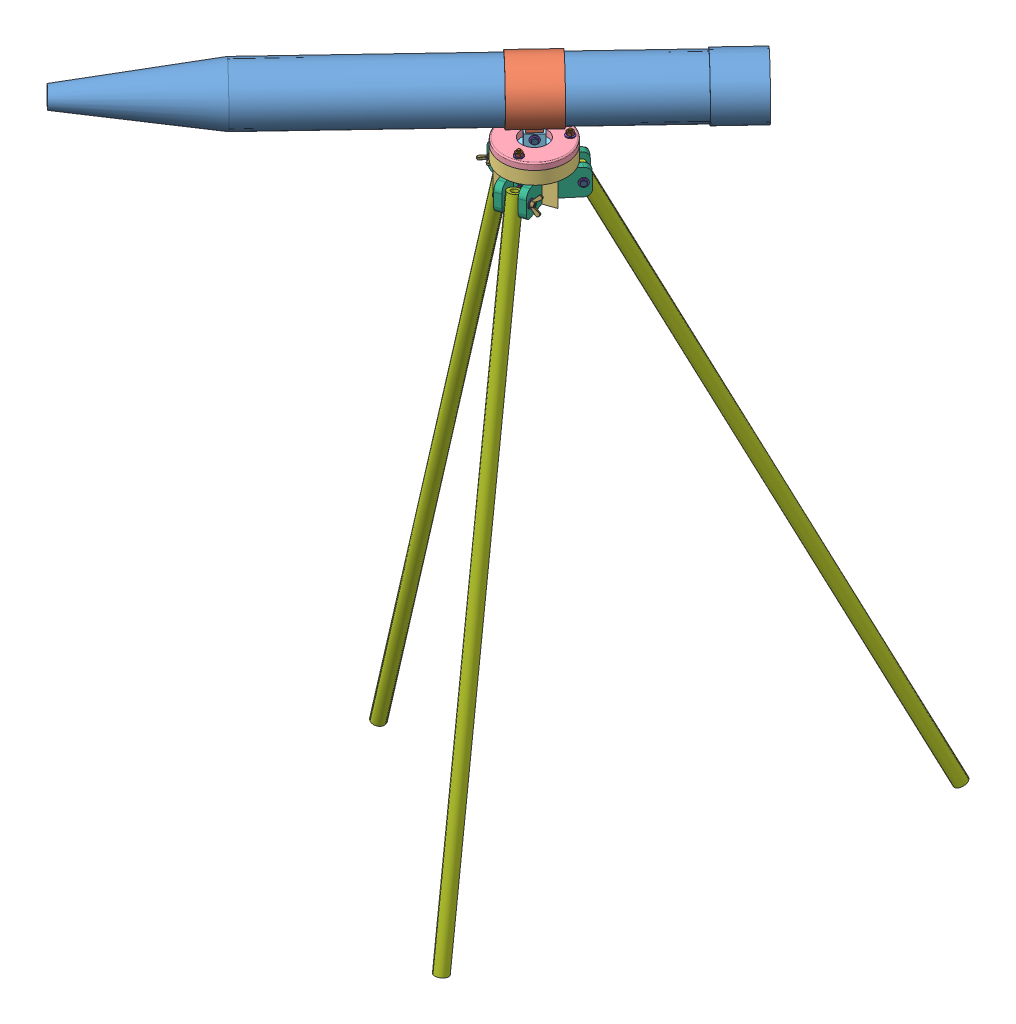
SolidWorks assembly ScopeAssembly, configuration Default. Lengths in mm.
Overall size (919.27 1388.64 1012.93).
45 component instances, 12 part files, 86 mates.
Components (placement in the parent):
- Scope-1: Scope [Default] at (13.0909 418.8257 1004.2832) x (-0.019653 -0.999634 -0.018601) z (0.726007 -0.02706 0.687155) size (111.76 1016 111.76)
- ScopeSupport-1: ScopeSupport [Default] at (455.0009 418.8257 537.3871) x (-0.726273 0 -0.687406) z (0.687406 0 -0.726273) size (113.03 157.48 84.67)
- RotatingDiskSeat-1: RotatingDiskSeat [Default] at (484.1011 298.1757 506.6415) x (0.762401 0 0.647105) z (-0.647105 0 0.762401) size (127 76.2 127)
- RotatingDiskLid-1: RotatingDiskLid [Default] at (484.1011 323.5757 506.6415) x (0.762401 0 0.647105) z (-0.647105 0 0.762401) size (127 12.7 127)
- RotatingDisk-1: RotatingDisk [Default] at (484.1011 310.8757 506.6415) x (0.687406 0 -0.726273) z (0.726273 0 0.687406) size (76.2 41.91 76.2)
- LegHinge-1: LegHinge [Default] at (502.5288 247.3757 558.1752) x (0.94161 0 -0.336706) z (0.336706 0 0.94161) size (50.8 50.8 50.8)
- LegHinge-2: LegHinge [Default] at (430.2577 298.1757 496.8335) x (0.179209 0 -0.983811) z (-0.983811 0 -0.179209) size (50.8 50.8 50.8)
- LegHinge-3: LegHinge [Default] at (519.5168 247.3757 464.9158) x (-0.762401 0 -0.647105) z (0.647105 0 -0.762401) size (50.8 50.8 50.8)
- Leg-1: Leg [Default] at (873.6454 -808.8425 47.6914) x (0.580125 0.443059 -0.683487) z (0.762401 0 0.647105) size (25.4 1219.2 25.4)
- Leg-2: Leg [Default] at (587.0814 -909.9329 794.6294) x (0.330066 0.19761 0.923042) z (-0.94161 0 0.336706) size (25.4 1219.2 25.4)
- Leg-3: Leg [Default] at (105.0997 -891.1144 437.6034) x (-0.949066 0.263414 -0.17288) z (0.179209 0 -0.983811) size (25.4 1219.2 25.4)
- flat washer type a narrow_ai-3: flat washer type a narrow_ai [Preferred Narrow FW 0.25] at (508.37 272.7757 438.7968) x (0.762401 0 0.647105) z (-0.647105 0 0.762401) size (1.65 15.88 15.88)
- flat washer type a narrow_ai-4: flat washer type a narrow_ai [Preferred Narrow FW 0.25] at (422.3152 272.7757 469.5687) x (-0.179209 0 0.983811) z (-0.983811 0 -0.179209) size (1.65 15.88 15.88)
- flat washer type a narrow_ai-5: flat washer type a narrow_ai [Preferred Narrow FW 0.25] at (530.7219 272.7757 561.5813) x (-0.94161 0 0.336706) z (-0.336706 0 -0.94161) size (1.65 15.88 15.88)
- flat washer type a narrow_ai-6: flat washer type a narrow_ai [Preferred Narrow FW 0.25] at (547.1 272.7757 471.6697) x (-0.762401 0 -0.647105) z (0.647105 0 -0.762401) size (1.65 15.88 15.88)
- flat washer type a narrow_ai-7: flat washer type a narrow_ai [Preferred Narrow FW 0.25] at (482.8881 272.7757 578.686) x (0.94161 0 -0.336706) z (0.336706 0 0.94161) size (1.65 15.88 15.88)
- flat washer type a narrow_ai-8: flat washer type a narrow_ai [Preferred Narrow FW 0.25] at (413.2114 272.7757 519.5463) x (0.179209 0 -0.983811) z (0.983811 0 0.179209) size (1.65 15.88 15.88)
- flat washer type a narrow_ai-9: flat washer type a narrow_ai [Preferred Narrow FW 0.25] at (442.7521 272.7757 499.1095) x (0.983811 0 0.179209) z (-0.179209 0 0.983811) size (1.65 15.88 15.88)
- flat washer type a narrow_ai-10: flat washer type a narrow_ai [Preferred Narrow FW 0.25] at (433.7081 298.1349 497.3786) x (0 1 0) z (0 0 1) size (1.65 15.88 15.88)
- flat washer type a narrow_ai-11: flat washer type a narrow_ai [Preferred Narrow FW 0.25] at (511.2985 272.7757 474.5982) x (-0.647105 0 0.762401) z (-0.762401 0 -0.647105) size (1.65 15.88 15.88)
- flat washer type a narrow_ai-12: flat washer type a narrow_ai [Preferred Narrow FW 0.25] at (516.974 298.1757 467.9115) x (0 1 0) z (0 0 1) size (1.65 15.88 15.88)
- flat washer type a narrow_ai-13: flat washer type a narrow_ai [Preferred Narrow FW 0.25] at (501.2058 298.1757 554.4753) x (0 1 0) z (0 0 1) size (1.65 15.88 15.88)
- flat washer type a narrow_ai-14: flat washer type a narrow_ai [Preferred Narrow FW 0.25] at (498.2526 272.7757 546.2168) x (-0.336706 0 -0.94161) z (0.94161 0 -0.336706) size (1.65 15.88 15.88)
- flat washer type a narrow_ai-15: flat washer type a narrow_ai [Preferred Narrow FW 0.25] at (501.2058 336.2757 554.4753) x (0 -1 0) z (0 0 1) size (1.65 15.88 15.88)
- flat washer type a narrow_ai-16: flat washer type a narrow_ai [Preferred Narrow FW 0.25] at (516.974 336.2757 467.9115) x (0 -1 0) z (0 0 1) size (1.65 15.88 15.88)
- flat washer type a narrow_ai-17: flat washer type a narrow_ai [Preferred Narrow FW 0.25] at (434.1235 336.2757 497.5377) x (0 -1 0) z (0 0 1) size (1.65 15.88 15.88)
- flat washer type a narrow_ai-18: flat washer type a narrow_ai [Preferred Narrow FW 0.25] at (472.5715 343.2607 495.7289) x (0.726273 0 0.687406) z (-0.687406 0 0.726273) size (1.65 15.88 15.88)
- flat washer type a narrow_ai-21: flat washer type a narrow_ai [Preferred Narrow FW 0.25] at (495.6307 343.2607 517.5541) x (-0.726273 0 -0.687406) z (0.687406 0 -0.726273) size (1.65 15.88 15.88)
- hex bolt_ai-7: hex bolt_ai [HBOLT 0.2500-20x2x0.75-N] at (433.7081 291.7087 497.3786) x (0 1 0) z (0 0 1) size (55.58 12.85 11.13)
- hex bolt_ai-8: hex bolt_ai [HBOLT 0.2500-20x2x0.75-N] at (516.974 291.7495 467.9115) x (0 1 0) z (0 0 1) size (55.58 12.85 11.13)
- hex bolt_ai-9: hex bolt_ai [HBOLT 0.2500-20x2x0.75-N] at (501.2058 291.7495 554.4753) x (0 1 0) z (0 0 1) size (55.58 12.85 11.13)
- hexagon head bolt (grade a)_ks-1: hexagon head bolt (grade a)_ks [KS 1002 A - M6 x 60 x 18-N] at (550.1496 272.7757 474.2582) x (-0.762401 0 -0.647105) z (0.647105 0 -0.762401) size (64 11.55 10)
- hexagon head bolt (grade a)_ks-2: hexagon head bolt (grade a)_ks [KS 1002 A - M6 x 60 x 18-N] at (423.0321 272.7757 465.6335) x (-0.179209 0 0.983811) z (-0.983811 0 -0.179209) size (64 11.55 10)
- hexagon head bolt (grade a)_ks-3: hexagon head bolt (grade a)_ks [KS 1002 A - M6 x 60 x 18-N] at (477.567 272.7757 580.5887) x (0.94161 0 -0.336706) z (0.336706 0 0.94161) size (64 11.55 10)
- hexagon head bolt (grade a)_ks-4: hexagon head bolt (grade a)_ks [KS 1002 A - M6 x 45 x 18-N] at (499.7348 343.2607 521.4386) x (-0.726273 0 -0.687406) z (0.687406 0 -0.726273) size (49 11.55 10)
- hex bolt_ai-14: hex bolt_ai [HBOLT 0.2500-20x1x0.75-N] at (499.8605 272.7757 550.7132) x (-0.336706 0 -0.94161) z (0.94161 0 -0.336706) size (30.18 12.85 11.13)
- hex bolt_ai-15: hex bolt_ai [HBOLT 0.2500-20x1x0.75-N] at (436.4299 272.7757 497.9578) x (0.983811 0 0.179209) z (-0.179209 0 0.983811) size (30.18 12.85 11.13)
- hex bolt_ai-16: hex bolt_ai [HBOLT 0.2500-20x1x0.75-N] at (515.4569 272.7757 469.6989) x (-0.647105 0 0.762401) z (-0.762401 0 -0.647105) size (30.18 12.85 11.13)
- hex nut_ai-2: hex nut_ai [HNUT 0.2500-20-D-N] at (501.2058 343.6671 554.4753) x (1 0 0) z (0 1 0) size (11.11 12.83 5.74)
- hex nut_ai-3: hex nut_ai [HNUT 0.2500-20-D-N] at (516.974 338.4418 467.9115) x (1 0 0) z (0 -1 0) size (11.11 12.83 5.74)
- hex nut_ai-4: hex nut_ai [HNUT 0.2500-20-D-N] at (433.7081 338.1349 497.3786) x (1 0 0) z (0 -1 0) size (11.11 12.83 5.74)
- wing nut (class 1)_ks-4: wing nut (class 1)_ks [KS B 1014-98 C1 - M6-N] at (471.3724 343.2607 494.594) x (-0.566242 0.566972 0.598258) z (-0.38974 -0.823737 0.411776) size (32 16 10.5)
- wing nut (class 1)_ks-7: wing nut (class 1)_ks [KS B 1014-98 C1 - M6-N] at (532.2765 272.7757 561.0254) x (0.113371 -0.94161 0.317046) z (0.317046 0.336706 0.886629) size (32 16 10.5)
- wing nut (class 1)_ks-8: wing nut (class 1)_ks [KS B 1014-98 C1 - M6-N] at (507.1113 272.7757 437.7284) x (0.418745 0.762401 -0.493353) z (-0.493353 0.647105 0.581255) size (32 16 10.5)
- wing nut (class 1)_ks-10: wing nut (class 1)_ks [KS B 1014-98 C1 - M6-N] at (412.9155 272.7757 521.1706) x (0.967884 0.179209 0.176308) z (0.176308 -0.983811 0.032116) size (32 16 10.5)
Mates (geometry in assembly coordinates):
- Concentric2: concentric anti-aligned: cylinder of Scope-1 through (39.1928 418.8257 976.7055) axis (-0.687406 0 0.726273) radius 53.34; cylinder of ScopeSupport-1 through (455.0009 418.8257 537.3871) axis (0.687406 0 -0.726273) radius 53.34
- Concentric3: concentric anti-aligned: cylinder of ScopeSupport-1 through (525.1464 343.2607 545.4903) axis (-0.726273 0 -0.687406) radius 3.175; cylinder of RotatingDisk-1 through (456.4301 343.2607 480.4513) axis (0.726273 0 0.687406) radius 3.175
- Parallel1: parallel aligned: plane of ScopeSupport-1 through (455.0009 317.8607 537.3871) normal (0 -1 0); plane of RotatingDisk-1 through (484.1011 310.8757 506.6415) normal (0 -1 0)
- Coincident3: coincident anti-aligned: plane of ScopeSupport-1 through (503.9776 362.3107 467.1659) normal (-0.726273 0 -0.687406); plane of RotatingDisk-1 through (466.1474 310.8757 507.1351) normal (0.726273 0 0.687406)
- Concentric4: concentric anti-aligned: cylinder of RotatingDiskSeat-1 through (484.1011 310.8757 506.6415) axis (0 1 0) radius 38.1; cylinder of RotatingDisk-1 through (484.1011 321.0357 506.6415) axis (0 -1 0) radius 38.1
- Coincident6: coincident anti-aligned: plane of RotatingDiskSeat-1 through (484.1011 310.8757 506.6415) normal (0 1 0); plane of RotatingDisk-1 through (484.1011 310.8757 506.6415) normal (0 -1 0)
- Concentric6: concentric aligned: cylinder of RotatingDiskSeat-1 through (501.2058 247.3757 554.4753) axis (0 1 0) radius 3.175; cylinder of RotatingDiskLid-1 through (501.2058 323.5757 554.4753) axis (0 1 0) radius 3.175
- Concentric7: concentric aligned: cylinder of RotatingDiskSeat-1 through (484.1011 323.5757 506.6415) axis (0 -1 0) radius 63.5; cylinder of RotatingDiskLid-1 through (484.1011 336.2757 506.6415) axis (0 -1 0) radius 63.5
- Coincident7: coincident anti-aligned: plane of RotatingDiskSeat-1 through (484.1011 323.5757 506.6415) normal (0 1 0); plane of RotatingDiskLid-1 through (484.1011 323.5757 506.6415) normal (0 -1 0)
- Coincident8: coincident aligned: circle of RotatingDiskSeat-1; circle of LegHinge-1
- Coincident9: coincident aligned: plane of RotatingDiskSeat-1 through (484.1011 247.3757 506.6415) normal (0 -1 0); plane of LegHinge-1 through (502.5288 247.3757 558.1752) normal (0 -1 0)
- Coincident11: coincident aligned: circle of RotatingDiskSeat-1; circle of LegHinge-2
- Coincident12: coincident anti-aligned: circle of RotatingDiskSeat-1; circle of LegHinge-3
- Coincident13: coincident aligned: plane of RotatingDiskSeat-1 through (484.1011 247.3757 506.6415) normal (0 -1 0); plane of LegHinge-2 through (430.2577 247.3757 496.8335) normal (0 -1 0)
- Coincident14: coincident aligned: plane of RotatingDiskSeat-1 through (484.1011 247.3757 506.6415) normal (0 -1 0); plane of LegHinge-3 through (519.5168 247.3757 464.9158) normal (0 -1 0)
- Concentric8: concentric anti-aligned: cylinder of LegHinge-1 through (482.8881 272.7757 578.686) axis (0.94161 0 -0.336706) radius 3.175; cylinder of Leg-2 through (518.7634 272.7757 565.8575) axis (-0.94161 0 0.336706) radius 3.175
- Width1: width: plane of LegHinge-1 through (499.1227 247.3757 586.3683) normal (0.94161 0 -0.336706); plane of LegHinge-1 through (523.0396 247.3757 577.816) normal (-0.94161 0 0.336706); cylinder of Leg-2 through (505.96 285.2252 567.7706) axis (0.066537 -0.980281 0.186072) radius 12.7
- Width2: width: plane of LegHinge-2 through (407.5449 298.1757 479.7872) normal (-0.179209 0 0.983811); plane of LegHinge-2 through (402.993 298.1757 504.776) normal (0.179209 0 -0.983811); cylinder of Leg-3 through (421.0545 285.0271 495.1571) axis (-0.259149 -0.964683 -0.047206) radius 12.7
- Width3: width: plane of LegHinge-3 through (545.6357 247.3757 453.769) normal (-0.762401 0 -0.647105); plane of LegHinge-3 through (526.2707 247.3757 437.3325) normal (0.762401 0 0.647105); cylinder of Leg-1 through (524.0938 284.1611 459.5232) axis (0.286706 -0.896492 -0.337789) radius 12.7
- Concentric9: concentric anti-aligned: cylinder of LegHinge-3 through (547.1 272.7757 471.6697) axis (-0.762401 0 -0.647105) radius 3.175; cylinder of Leg-1 through (518.0525 272.7757 447.015) axis (0.762401 0 0.647105) radius 3.175
- Concentric10: concentric aligned: cylinder of LegHinge-2 through (413.2114 272.7757 519.5463) axis (0.179209 0 -0.983811) radius 3.175; cylinder of Leg-3 through (415.4874 272.7757 507.0519) axis (0.179209 0 -0.983811) radius 3.175
- LimitDistance1: limit distance = 203.8008 mm anti-aligned: plane of ScopeSupport-1 through (513.2013 418.8257 475.8959) normal (0.687406 0 -0.726273); plane of Scope-1 through (652.197 362.9661 326.8414) normal (-0.687406 0 0.726273)
- Concentric11: concentric aligned: cylinder of LegHinge-3 through (547.1 272.7757 471.6697) axis (-0.762401 0 -0.647105) radius 3.175; cylinder of flat washer type a narrow_ai-3 through (481.7432 272.7757 416.1967) axis (-0.762401 0 -0.647105) radius 3.5687
- Coincident15: coincident anti-aligned: plane of LegHinge-3 through (516.5882 298.1757 429.1143) normal (-0.762401 0 -0.647105); plane of flat washer type a narrow_ai-3 through (508.37 276.3444 438.7968) normal (0.762401 0 0.647105)
- Concentric12: concentric aligned: cylinder of LegHinge-2 through (413.2114 272.7757 519.5463) axis (0.179209 0 -0.983811) radius 3.175; cylinder of flat washer type a narrow_ai-4 through (428.5741 272.7757 435.2091) axis (0.179209 0 -0.983811) radius 3.5687
- Coincident16: coincident anti-aligned: plane of LegHinge-2 through (409.8208 247.3757 467.2928) normal (0.179209 0 -0.983811); plane of flat washer type a narrow_ai-4 through (422.3152 276.3444 469.5687) normal (-0.179209 0 0.983811)
- Concentric13: concentric aligned: cylinder of LegHinge-1 through (482.8881 272.7757 578.686) axis (0.94161 0 -0.336706) radius 3.175; cylinder of flat washer type a narrow_ai-5 through (563.6076 272.7757 549.8219) axis (0.94161 0 -0.336706) radius 3.5687
- Coincident17: coincident anti-aligned: plane of LegHinge-1 through (534.998 298.1757 573.5398) normal (0.94161 0 -0.336706); plane of flat washer type a narrow_ai-5 through (530.7219 276.3444 561.5813) normal (-0.94161 0 0.336706)
- Concentric14: concentric anti-aligned: cylinder of LegHinge-3 through (547.1 272.7757 471.6697) axis (-0.762401 0 -0.647105) radius 3.175; cylinder of flat washer type a narrow_ai-6 through (573.7268 272.7757 494.2699) axis (0.762401 0 0.647105) radius 3.5687
- Coincident18: coincident anti-aligned: plane of LegHinge-3 through (555.3182 298.1757 461.9872) normal (0.762401 0 0.647105); plane of flat washer type a narrow_ai-6 through (547.1 276.3444 471.6697) normal (-0.762401 0 -0.647105)
- Concentric15: concentric anti-aligned: cylinder of LegHinge-1 through (482.8881 272.7757 578.686) axis (0.94161 0 -0.336706) radius 3.175; cylinder of flat washer type a narrow_ai-7 through (450.0024 272.7757 590.4455) axis (-0.94161 0 0.336706) radius 3.5687
- Coincident19: coincident anti-aligned: plane of LegHinge-1 through (487.1642 298.1757 590.6445) normal (-0.94161 0 0.336706); plane of flat washer type a narrow_ai-7 through (482.8881 276.3444 578.686) normal (0.94161 0 -0.336706)
- Concentric16: concentric anti-aligned: cylinder of LegHinge-2 through (413.2114 272.7757 519.5463) axis (0.179209 0 -0.983811) radius 3.175; cylinder of flat washer type a narrow_ai-8 through (406.9525 272.7757 553.9059) axis (-0.179209 0 0.983811) radius 3.5687
- Coincident20: coincident anti-aligned: plane of LegHinge-2 through (400.717 247.3757 517.2704) normal (-0.179209 0 0.983811); plane of flat washer type a narrow_ai-8 through (413.2114 276.3444 519.5463) normal (0.179209 0 -0.983811)
- Concentric17: concentric aligned: cylinder of LegHinge-2 through (455.2465 272.7757 501.3854) axis (-0.983811 0 -0.179209) radius 3.175; cylinder of flat washer type a narrow_ai-9 through (408.3925 272.7757 492.8506) axis (-0.983811 0 -0.179209) radius 3.5687
- Coincident21: coincident anti-aligned: plane of LegHinge-2 through (440.4762 298.1757 511.6039) normal (-0.983811 0 -0.179209); plane of flat washer type a narrow_ai-9 through (442.7521 276.3444 499.1095) normal (0.983811 0 0.179209)
- Concentric18: concentric aligned: cylinder of LegHinge-3 through (503.0803 272.7757 484.2807) axis (0.647105 0 -0.762401) radius 3.175; cylinder of flat washer type a narrow_ai-11 through (533.8987 272.7757 447.9714) axis (0.647105 0 -0.762401) radius 3.5687
- Coincident22: coincident anti-aligned: plane of LegHinge-3 through (520.981 247.3757 482.8165) normal (0.647105 0 -0.762401); plane of flat washer type a narrow_ai-11 through (511.2985 276.3444 474.5982) normal (-0.647105 0 0.762401)
- Concentric19: concentric anti-aligned: cylinder of RotatingDiskSeat-1 through (516.974 247.3757 467.9115) axis (0 1 0) radius 3.175; cylinder of flat washer type a narrow_ai-12 through (516.974 263.2507 467.9115) axis (0 -1 0) radius 3.5687
- Coincident23: coincident anti-aligned: plane of RotatingDiskSeat-1 through (484.1011 298.1757 506.6415) normal (0 -1 0); plane of flat washer type a narrow_ai-12 through (513.4053 298.1757 467.9115) normal (0 1 0)
- Concentric20: concentric anti-aligned: cylinder of RotatingDiskSeat-1 through (501.2058 247.3757 554.4753) axis (0 1 0) radius 3.175; cylinder of flat washer type a narrow_ai-13 through (501.2058 263.2507 554.4753) axis (0 -1 0) radius 3.5687
- Coincident24: coincident anti-aligned: plane of RotatingDiskSeat-1 through (484.1011 298.1757 506.6415) normal (0 -1 0); plane of flat washer type a narrow_ai-13 through (497.6371 298.1757 554.4753) normal (0 1 0)
- Concentric21: concentric aligned: cylinder of LegHinge-1 through (493.9765 272.7757 534.2583) axis (0.336706 0 0.94161) radius 3.175; cylinder of flat washer type a narrow_ai-14 through (510.0121 272.7757 579.1025) axis (0.336706 0 0.94161) radius 3.5687
- Coincident25: coincident anti-aligned: plane of LegHinge-1 through (486.2942 247.3757 550.493) normal (0.336706 0 0.94161); plane of flat washer type a narrow_ai-14 through (498.2526 276.3444 546.2168) normal (-0.336706 0 -0.94161)
- Concentric22: concentric aligned: cylinder of RotatingDiskLid-1 through (501.2058 323.5757 554.4753) axis (0 1 0) radius 3.175; cylinder of flat washer type a narrow_ai-15 through (501.2058 371.2007 554.4753) axis (0 1 0) radius 3.5687
- Coincident26: coincident anti-aligned: plane of RotatingDiskLid-1 through (484.1011 336.2757 506.6415) normal (0 1 0); plane of flat washer type a narrow_ai-15 through (504.7745 336.2757 554.4753) normal (0 -1 0)
- Concentric23: concentric aligned: cylinder of RotatingDiskLid-1 through (516.974 323.5757 467.9115) axis (0 1 0) radius 3.175; cylinder of flat washer type a narrow_ai-16 through (516.974 371.2007 467.9115) axis (0 1 0) radius 3.5687
- Coincident27: coincident anti-aligned: plane of RotatingDiskLid-1 through (484.1011 336.2757 506.6415) normal (0 1 0); plane of flat washer type a narrow_ai-16 through (520.5427 336.2757 467.9115) normal (0 -1 0)
- Concentric24: concentric aligned: cylinder of RotatingDiskLid-1 through (434.1235 323.5757 497.5377) axis (0 1 0) radius 3.175; cylinder of flat washer type a narrow_ai-17 through (434.1235 371.2007 497.5377) axis (0 1 0) radius 3.5687
- Coincident28: coincident anti-aligned: plane of RotatingDiskLid-1 through (484.1011 336.2757 506.6415) normal (0 1 0); plane of flat washer type a narrow_ai-17 through (437.6922 336.2757 497.5377) normal (0 -1 0)
- Concentric28: concentric aligned: cylinder of flat washer type a narrow_ai-10 through (433.7081 263.2099 497.3786) axis (0 -1 0) radius 3.5687; cylinder of hex bolt_ai-7 through (433.7081 291.7087 497.3786) axis (0 -1 0) radius 3.175
- Coincident32: coincident anti-aligned: plane of flat washer type a narrow_ai-10 through (425.7706 296.4839 497.3786) normal (0 -1 0); plane of hex bolt_ai-7 through (427.285 296.4839 497.3786) normal (0 1 0)
- Concentric29: concentric anti-aligned: cylinder of RotatingDiskSeat-1 through (516.974 247.3757 467.9115) axis (0 1 0) radius 3.175; cylinder of hex bolt_ai-8 through (516.974 291.7495 467.9115) axis (0 -1 0) radius 3.175
- Coincident33: coincident anti-aligned: plane of flat washer type a narrow_ai-12 through (509.0365 296.5247 467.9115) normal (0 -1 0); plane of hex bolt_ai-8 through (510.5509 296.5247 467.9115) normal (0 1 0)
- Concentric30: concentric anti-aligned: cylinder of RotatingDiskSeat-1 through (501.2058 247.3757 554.4753) axis (0 1 0) radius 3.175; cylinder of hex bolt_ai-9 through (501.2058 291.7495 554.4753) axis (0 -1 0) radius 3.175
- Coincident34: coincident anti-aligned: plane of flat washer type a narrow_ai-13 through (493.2683 296.5247 554.4753) normal (0 -1 0); plane of hex bolt_ai-9 through (494.7826 296.5247 554.4753) normal (0 1 0)
- Concentric31: concentric anti-aligned: cylinder of RotatingDisk-1 through (456.4301 343.2607 480.4513) axis (0.726273 0 0.687406) radius 3.175; cylinder of flat washer type a narrow_ai-18 through (447.2064 343.2607 471.7213) axis (-0.726273 0 -0.687406) radius 3.5687
- Coincident35: coincident anti-aligned: plane of RotatingDisk-1 through (483.4841 352.7857 484.1993) normal (-0.726273 0 -0.687406); plane of flat washer type a narrow_ai-18 through (472.5715 346.8294 495.7289) normal (0.726273 0 0.687406)
- Concentric35: concentric aligned: cylinder of RotatingDisk-1 through (456.4301 343.2607 480.4513) axis (0.726273 0 0.687406) radius 3.175; cylinder of flat washer type a narrow_ai-21 through (520.9958 343.2607 541.5617) axis (0.726273 0 0.687406) radius 3.5687
- Coincident37: coincident anti-aligned: plane of RotatingDisk-1 through (506.5433 352.7857 506.0245) normal (0.726273 0 0.687406); plane of flat washer type a narrow_ai-21 through (495.6307 346.8294 517.5541) normal (-0.726273 0 -0.687406)
- Concentric37: concentric anti-aligned: cylinder of hex bolt_ai-9 through (501.2058 291.7495 554.4753) axis (0 -1 0) radius 3.175; cylinder of hex nut_ai-2 through (501.2058 318.6296 554.4753) axis (0 1 0) radius 3.175
- Coincident39: coincident anti-aligned: plane of flat washer type a narrow_ai-15 through (509.1433 337.9267 554.4753) normal (0 1 0); plane of hex nut_ai-2 through (501.2058 337.9267 548.0595) normal (0 -1 0)
- Concentric38: concentric aligned: cylinder of hex bolt_ai-8 through (516.974 291.7495 467.9115) axis (0 -1 0) radius 3.175; cylinder of hex nut_ai-3 through (516.974 363.4793 467.9115) axis (0 -1 0) radius 3.175
- Concentric39: concentric aligned: cylinder of hex bolt_ai-7 through (433.7081 291.7087 497.3786) axis (0 -1 0) radius 3.175; cylinder of hex nut_ai-4 through (433.7081 363.1724 497.3786) axis (0 -1 0) radius 3.175
- Concentric40: concentric anti-aligned: cylinder of LegHinge-3 through (547.1 272.7757 471.6697) axis (-0.762401 0 -0.647105) radius 3.175; cylinder of hexagon head bolt (grade a)_ks-1 through (550.1496 272.7757 474.2582) axis (0.762401 0 0.647105) radius 5
- Coincident40: coincident anti-aligned: plane of LegHinge-3 through (555.3182 298.1757 461.9872) normal (0.762401 0 0.647105); plane of hexagon head bolt (grade a)_ks-1 through (543.8644 281.4359 475.4817) normal (-0.762401 0 -0.647105)
- Concentric411: concentric aligned: cylinder of LegHinge-2 through (413.2114 272.7757 519.5463) axis (0.179209 0 -0.983811) radius 3.175; cylinder of hexagon head bolt (grade a)_ks-2 through (423.0321 272.7757 465.6335) axis (0.179209 0 -0.983811) radius 5
- Coincident411: coincident anti-aligned: plane of LegHinge-2 through (409.8208 247.3757 467.2928) normal (0.179209 0 -0.983811); plane of hexagon head bolt (grade a)_ks-2 through (427.2343 281.4359 470.4648) normal (-0.179209 0 0.983811)
- Concentric42: concentric aligned: cylinder of flat washer type a narrow_ai-7 through (450.0024 272.7757 590.4455) axis (-0.94161 0 0.336706) radius 7.9375; cylinder of hexagon head bolt (grade a)_ks-3 through (477.567 272.7757 580.5887) axis (-0.94161 0 0.336706) radius 5
- Coincident42: coincident anti-aligned: plane of flat washer type a narrow_ai-7 through (481.3335 280.7132 579.2419) normal (-0.94161 0 0.336706); plane of hexagon head bolt (grade a)_ks-3 through (479.65 281.4359 574.5339) normal (0.94161 0 -0.336706)
- Concentric43: concentric aligned: cylinder of RotatingDisk-1 through (456.4301 343.2607 480.4513) axis (0.726273 0 0.687406) radius 3.175; cylinder of hexagon head bolt (grade a)_ks-4 through (499.7348 343.2607 521.4386) axis (0.726273 0 0.687406) radius 5
- Coincident43: coincident anti-aligned: plane of flat washer type a narrow_ai-21 through (496.8298 351.1982 518.689) normal (0.726273 0 0.687406); plane of hexagon head bolt (grade a)_ks-4 through (493.3927 351.9209 522.3203) normal (-0.726273 0 -0.687406)
- Concentric44: concentric aligned: cylinder of flat washer type a narrow_ai-18 through (447.2064 343.2607 471.7213) axis (-0.726273 0 -0.687406) radius 3.5687; cone of wing nut (class 1)_ks-4 through (471.3724 343.2607 494.594) axis (-0.726273 0 -0.687406)
- Coincident44: coincident anti-aligned: plane of flat washer type a narrow_ai-18 through (471.3724 351.1982 494.594) normal (-0.726273 0 -0.687406); plane of wing nut (class 1)_ks-4 through (471.3724 343.2607 494.594) normal (0.726273 0 0.687406)
- Concentric46: concentric aligned: cylinder of flat washer type a narrow_ai-5 through (563.6076 272.7757 549.8219) axis (0.94161 0 -0.336706) radius 3.5687; cone of wing nut (class 1)_ks-7 through (532.2765 272.7757 561.0254) axis (0.94161 0 -0.336706)
- Coincident46: coincident anti-aligned: plane of flat washer type a narrow_ai-5 through (532.2765 280.7132 561.0254) normal (0.94161 0 -0.336706); plane of wing nut (class 1)_ks-7 through (532.2765 272.7757 561.0254) normal (-0.94161 0 0.336706)
- Concentric47: concentric aligned: cylinder of flat washer type a narrow_ai-3 through (481.7432 272.7757 416.1967) axis (-0.762401 0 -0.647105) radius 7.9375; cone of wing nut (class 1)_ks-8 through (507.1113 272.7757 437.7284) axis (-0.762401 0 -0.647105)
- Coincident47: coincident anti-aligned: plane of flat washer type a narrow_ai-3 through (507.1113 280.7132 437.7284) normal (-0.762401 0 -0.647105); plane of wing nut (class 1)_ks-8 through (507.1113 272.7757 437.7284) normal (0.762401 0 0.647105)
- Concentric48: concentric aligned: cylinder of flat washer type a narrow_ai-8 through (406.9525 272.7757 553.9059) axis (-0.179209 0 0.983811) radius 3.5687; cone of wing nut (class 1)_ks-10 through (412.9155 272.7757 521.1706) axis (-0.179209 0 0.983811)
- Coincident48: coincident anti-aligned: plane of flat washer type a narrow_ai-8 through (412.9155 280.7132 521.1706) normal (-0.179209 0 0.983811); plane of wing nut (class 1)_ks-10 through (412.9155 272.7757 521.1706) normal (0.179209 0 -0.983811)
- Concentric49: concentric aligned: cylinder of LegHinge-1 through (493.9765 272.7757 534.2583) axis (0.336706 0 0.94161) radius 3.175; cylinder of hex bolt_ai-14 through (499.8605 272.7757 550.7132) axis (0.336706 0 0.94161) radius 3.175
- Coincident49: coincident anti-aligned: plane of LegHinge-1 through (486.2942 247.3757 550.493) normal (0.336706 0 0.94161); plane of hex bolt_ai-14 through (498.2526 279.1988 546.2168) normal (-0.336706 0 -0.94161)
- Concentric50: concentric aligned: cylinder of flat washer type a narrow_ai-9 through (408.3925 272.7757 492.8506) axis (-0.983811 0 -0.179209) radius 7.9375; cylinder of hex bolt_ai-15 through (436.4299 272.7757 497.9578) axis (-0.983811 0 -0.179209) radius 3.175
- Coincident50: coincident anti-aligned: plane of flat washer type a narrow_ai-9 through (441.1278 280.7132 498.8136) normal (-0.983811 0 -0.179209); plane of hex bolt_ai-15 through (441.1278 279.1988 498.8136) normal (0.983811 0 0.179209)
- Concentric51: concentric aligned: cylinder of LegHinge-3 through (503.0803 272.7757 484.2807) axis (0.647105 0 -0.762401) radius 3.175; cylinder of hex bolt_ai-16 through (515.4569 272.7757 469.6989) axis (0.647105 0 -0.762401) radius 3.175
- Coincident51: coincident anti-aligned: plane of flat washer type a narrow_ai-11 through (512.3669 280.7132 473.3395) normal (0.647105 0 -0.762401); plane of hex bolt_ai-16 through (512.3669 279.1988 473.3395) normal (-0.647105 0 0.762401)
